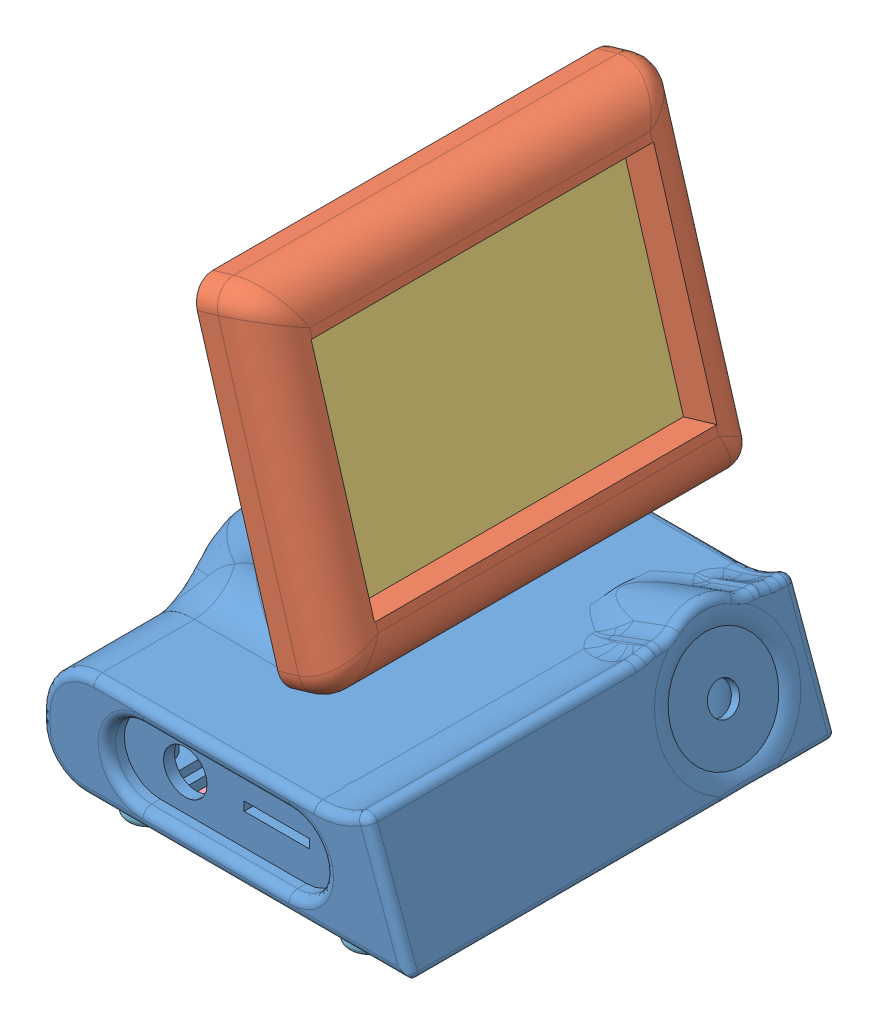
SolidWorks assembly Сборка2, configuration По умолчанию. Lengths in mm.
Overall size (85.25 122.29 98).
8 component instances, 5 part files, 13 mates.
Components (placement in the parent):
- Приемник_Корпус-1: Приемник_Корпус [По умолчанию] at (-7.2521 -39.4297 -50) size (85.25 107.61 98)
- Приемник-1: Приемник [По умолчанию] at (-7.2746 25.6822 -1) x (0 0 1) z (-0.284554 0.95866 0) size (98 15 75)
- крышка приемник-1: крышка приемник [По умолчанию] at (-7.2746 25.6822 -1) x (0 0 -1) z (0.284554 -0.95866 0) size (95.5 5 72.5)
- корпус крышка-1: корпус крышка [По умолчанию] at (-10.3821 -50.3934 -1) x (0 0 1) z (1 0 0) size (92 5 60.74)
- ножки_корпус_приемник-1: ножки_корпус_приемник [По умолчанию] at (-35.7521 -56.3934 40) size (10 4 10)
- ножки_корпус_приемник-2: ножки_корпус_приемник [По умолчанию] at (14.9879 -56.3934 40) size (10 4 10)
- ножки_корпус_приемник-3: ножки_корпус_приемник [По умолчанию] at (-35.7521 -56.3934 -42) size (10 4 10)
- ножки_корпус_приемник-4: ножки_корпус_приемник [По умолчанию] at (14.9879 -56.3934 -42) size (10 4 10)
Mates (geometry in assembly coordinates):
- Совпадение18: coincident: line of Приемник-1 through (-17.5897 60.4336 43.75) axis (0 0 -1); line of крышка приемник-1 through (-17.5897 60.4336 -45.75) axis (0 0 1)
- Совпадение19: coincident: line of Приемник-1 through (2.1868 -6.1932 46.75) axis (-0.284554 0.95866 0); line of крышка приемник-1 through (-16.736 57.5577 46.75) axis (0.284554 -0.95866 0)
- Совпадение36: coincident: point of Приемник_Корпус-1; point of крышка приемник-1
- Касательность1: tangent: plane of корпус крышка-1 through (-10.3821 -52.3934 -1) normal (0 -1 0); circle of ножки_корпус_приемник-1
- Совпадение37: coincident: line of Приемник_Корпус-1 through (19.9912 -52.3934 45) axis (-1 0 0); line of корпус крышка-1 through (19.9879 -52.3934 45) axis (-1 0 0)
- Совпадение38: coincident: line of Приемник_Корпус-1 through (-40.7521 -52.3934 45) axis (0 0 -1); line of корпус крышка-1 through (-40.7521 -52.3934 45) axis (0 0 -1)
- Концентричный6: concentric: circle of корпус крышка-1; circle of ножки_корпус_приемник-1
- Касательность2: tangent: plane of корпус крышка-1 through (-10.3821 -52.3934 -1) normal (0 -1 0); circle of ножки_корпус_приемник-2
- Концентричный8: concentric: circle of корпус крышка-1; circle of ножки_корпус_приемник-2
- Касательность3: tangent: plane of корпус крышка-1 through (-10.3821 -52.3934 -1) normal (0 -1 0); circle of ножки_корпус_приемник-3
- Концентричный9: concentric: circle of корпус крышка-1; circle of ножки_корпус_приемник-3
- Касательность4: tangent: plane of корпус крышка-1 through (-10.3821 -52.3934 -1) normal (0 -1 0); circle of ножки_корпус_приемник-4
- Концентричный11: concentric: circle of корпус крышка-1; circle of ножки_корпус_приемник-4
